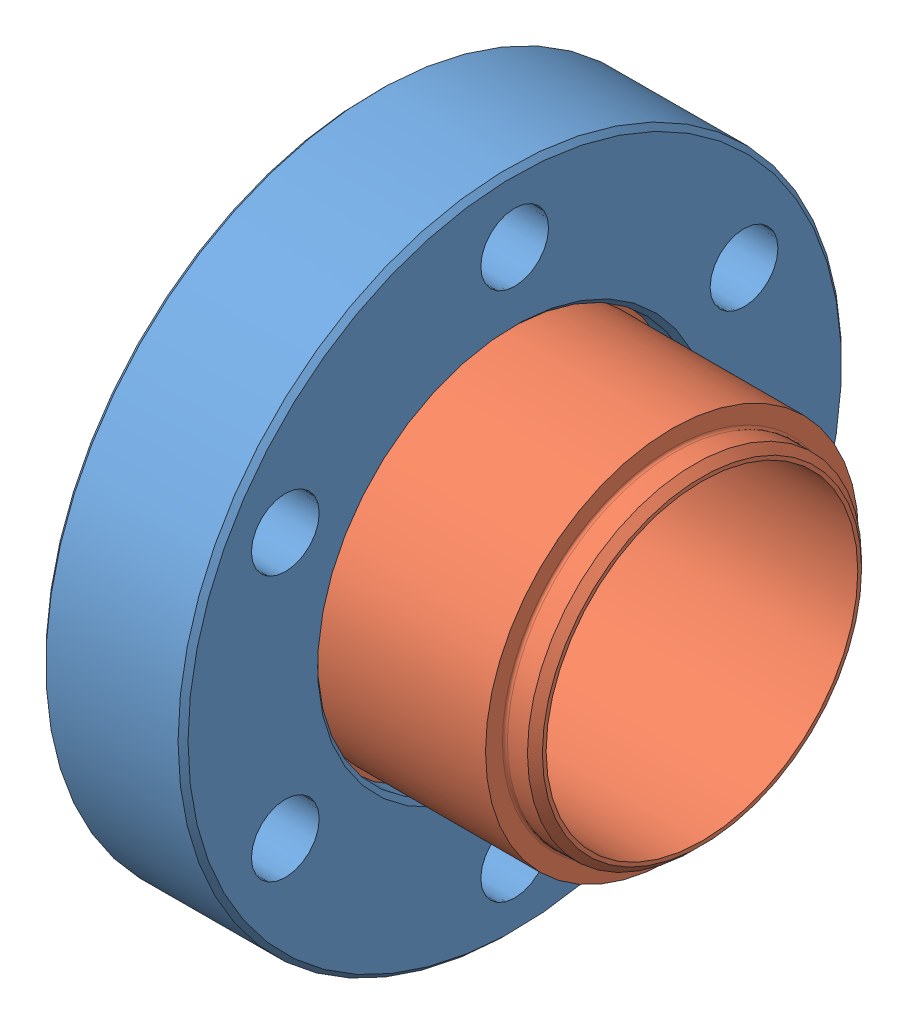
SolidWorks assembly 120004, configuration Default. Lengths in mm.
Overall size (16.78 33.78 33.78).
2 component instances, 2 part files, 2 mates.
Components (placement in the parent):
- 920000-1: 920000 [Default] at (8.0909 19.2498 25.3043) size (7.24 33.78 33.78)
- 910004-1: 910004 [Default] at (11.3548 19.2498 25.3043) size (13.46 21.29 21.29)
Mates (geometry in assembly coordinates):
- Concentric1: concentric aligned: cylinder of 920000-1 through (8.0909 19.2498 25.3043) axis (-1 0 0) radius 16.891; cylinder of 910004-1 through (11.3548 19.2498 25.3043) axis (-1 0 0) radius 9.4996
- Coincident1: coincident anti-aligned: plane of 920000-1 through (13.9329 29.9686 25.3043) normal (-1 0 0); plane of 910004-1 through (13.9329 29.8924 25.3043) normal (1 0 0)
